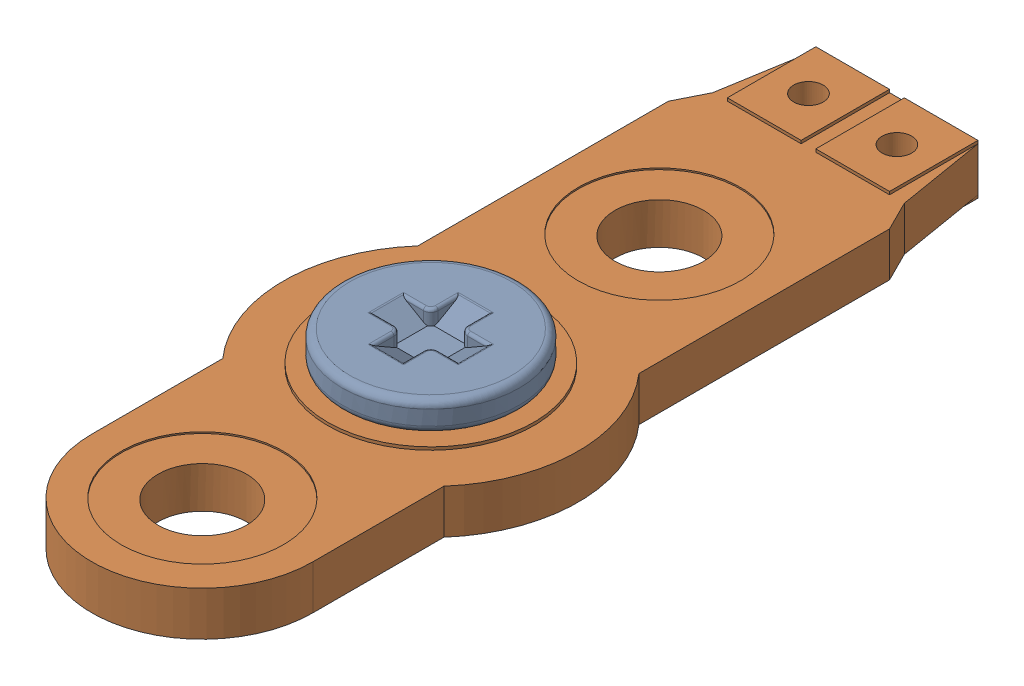
SolidWorks assembly screw switch switch screw switch, configuration Default. Lengths in mm.
Overall size (10 4.5 27.31).
2 component instances, 2 part files, 6 mates.
Components (placement in the parent):
- screw switch screw screw-1: screw switch screw screw [Default] at (0 2.6 0) size (6 4.5 6)
- screw switch switch switch-1: screw switch switch switch [Default] at origin size (10 3.1 27.31)
Mates (geometry in assembly coordinates):
- Coincident1: coincident anti-aligned: plane of screw switch switch-1 through (0 0 7.75) normal (0 -1 0)
- Coincident2: coincident: point of screw switch switch-1
- Coincident3: coincident: unknown of screw switch switch-1
- Parallel1: parallel aligned: plane of screw switch switch-1 through (3.75 1.5 7.75) normal (1 0 0)
- Concentric2: concentric: cylinder of screw switch screw-1 through (0 -214.6459 0) axis (0 -1 0) radius 1.25; cylinder of screw switch switch-1 through (0 1.5 0) axis (0 -1 0) radius 1.5
- Coincident5: coincident anti-aligned: plane of screw switch screw-1 through (3 1.6 0) normal (0 -1 0); plane of screw switch switch-1 through (0 1.6 0) normal (0 1 0)
